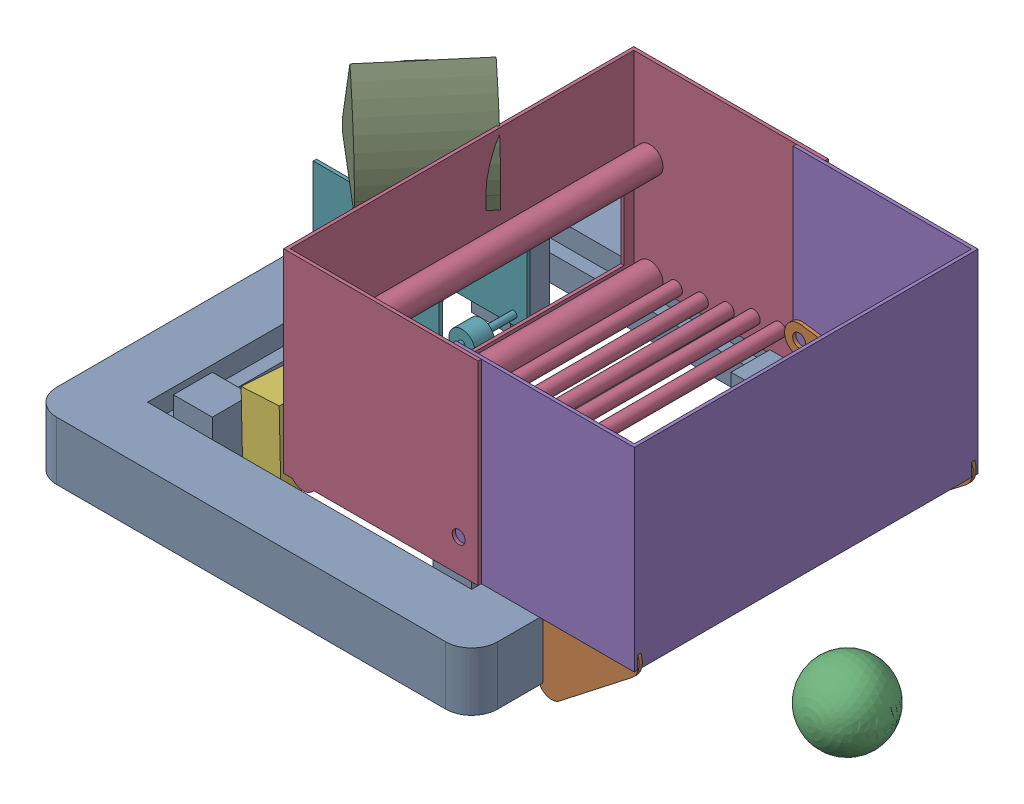
SolidWorks assembly ROBOT CRAYOLA CAD, configuration Default. Lengths in mm.
Overall size (1316.56 603.63 939.8).
8 component instances, 8 part files, 13 mates.
Components (placement in the parent):
- CRAYOLA CAD Robot Frame-1: CRAYOLA CAD Robot Frame [Default] at (652.713 854.3901 1264.9275) size (863.6 152.4 939.8)
- CRAYOLA CAD Over Bumper Intake-1: CRAYOLA CAD Over Bumper Intake [Default] at (1101.1588 834.5121 934.7275) x (0 0 1) z (-0.998639 0.05215 0) size (660.4 217.2 371.48)
- FUEL-1: FUEL [Default] at (1461.2733 874.4838 1375.9498) size (152.4 152.4 152.4)
- Storage-Hopper Part1-1: Storage-Hopper Part1 [Default] at (589.213 943.2901 1607.8275) size (381 391.5 685.8)
- Storage-Hopper Part2-1: Storage-Hopper Part2 [Default] at (1269.7552 943.2901 1601.4775) size (355.6 381 673.1)
- Battery-2: Battery [Default] at (514.8483 854.0267 1485.2361) x (-0.021236 0.046906 0.998674) z (-0.997204 -0.072577 -0.017796) size (177.8 152.4 76.2)
- Shooter Transition-Transfer-Kicker-1: Shooter Transition-Transfer-Kicker [Default] at (342.312 943.2901 1214.1275) x (0 0 1) z (-1 0 0) size (177.8 260.35 246.9)
- Hood-1: Hood [Default] at (465.7625 1197.2901 1214.1275) x (-0.647583 0 0.761995) z (-0.761995 0 -0.647583) size (203.2 204.62 241.3)
Mates (geometry in assembly coordinates):
- Width1: width aligned: plane of CRAYOLA CAD Over Bumper Intake-1 through (1101.1588 834.5121 1595.1275) normal (0 0 1); plane of CRAYOLA CAD Robot Frame-1 through (1101.1588 834.5121 934.7275) normal (0 0 -1); plane of CRAYOLA CAD Over Bumper Intake-1 through (652.713 905.1901 934.7275) normal (0 0 1); plane of CRAYOLA CAD Robot Frame-1 through (652.713 905.1901 1595.1275) normal (0 0 -1)
- Width2: width anti-aligned: plane of Storage-Hopper Part2-1 through (1269.7552 1324.2901 928.3775) normal (0 0 -1); plane of Storage-Hopper Part1-1 through (1269.7552 1324.2901 1601.4775) normal (0 0 1); plane of Storage-Hopper Part2-1 through (589.213 1324.2901 1607.8275) normal (0 0 1); plane of Storage-Hopper Part1-1 through (589.213 1324.2901 922.0275) normal (0 0 -1)
- Coincident7: coincident aligned: plane of Storage-Hopper Part1-1 through (589.213 1324.2901 1607.8275) normal (0 1 0); plane of Storage-Hopper Part2-1 through (1269.7552 1324.2901 1601.4775) normal (0 1 0)
- Coincident8: coincident anti-aligned: plane of CRAYOLA CAD Robot Frame-1 through (652.713 943.2901 1264.9275) normal (0 1 0); plane of Storage-Hopper Part1-1 through (589.213 943.2901 1607.8275) normal (0 -1 0)
- Width3: width anti-aligned: plane of CRAYOLA CAD Robot Frame-1 through (220.913 828.9901 1734.8275) normal (0 0 1); plane of Storage-Hopper Part1-1 through (1084.513 828.9901 795.0275) normal (0 0 -1); plane of CRAYOLA CAD Robot Frame-1 through (589.213 1324.2901 922.0275) normal (0 0 -1); plane of Storage-Hopper Part1-1 through (589.213 1324.2901 1607.8275) normal (0 0 1)
- Coincident10: coincident: line of CRAYOLA CAD Robot Frame-1 through (970.213 943.2901 1620.5275) axis (0 0 -1); plane of Storage-Hopper Part1-1 through (970.213 1324.2901 1607.8275) normal (1 0 0)
- Concentric2: concentric anti-aligned: circle of CRAYOLA CAD Over Bumper Intake-1; circle of Storage-Hopper Part1-1
- Coincident14: coincident anti-aligned: plane of Storage-Hopper Part1-1 through (589.213 1324.2901 1607.8275) normal (-1 0 0); plane of Shooter Transition-Transfer-Kicker-1 through (589.213 943.2901 1303.0275) normal (1 0 0)
- Parallel1: parallel aligned: line of Storage-Hopper Part1-1 through (589.213 943.2901 1607.8275) axis (1 0 0); line of Shooter Transition-Transfer-Kicker-1 through (342.312 943.2901 1303.0275) axis (1 0 0)
- Coincident16: coincident aligned: plane of Storage-Hopper Part1-1 through (589.213 943.2901 1607.8275) normal (0 -1 0); plane of Shooter Transition-Transfer-Kicker-1 through (342.312 943.2901 1303.0275) normal (0 -1 0)
- Coincident17: coincident anti-aligned: plane of Shooter Transition-Transfer-Kicker-1 through (342.312 1197.2901 1303.0275) normal (0 1 0); plane of Hood-1 through (465.7625 1197.2901 1214.1275) normal (0 -1 0)
- Concentric9: concentric anti-aligned: circle of Shooter Transition-Transfer-Kicker-1; circle of Hood-1
- Distance1: distance = 304.8 mm aligned: plane of Shooter Transition-Transfer-Kicker-1 through (342.312 943.2901 1303.0275) normal (0 0 1); plane of Storage-Hopper Part1-1 through (589.213 1324.2901 1607.8275) normal (0 0 1)
